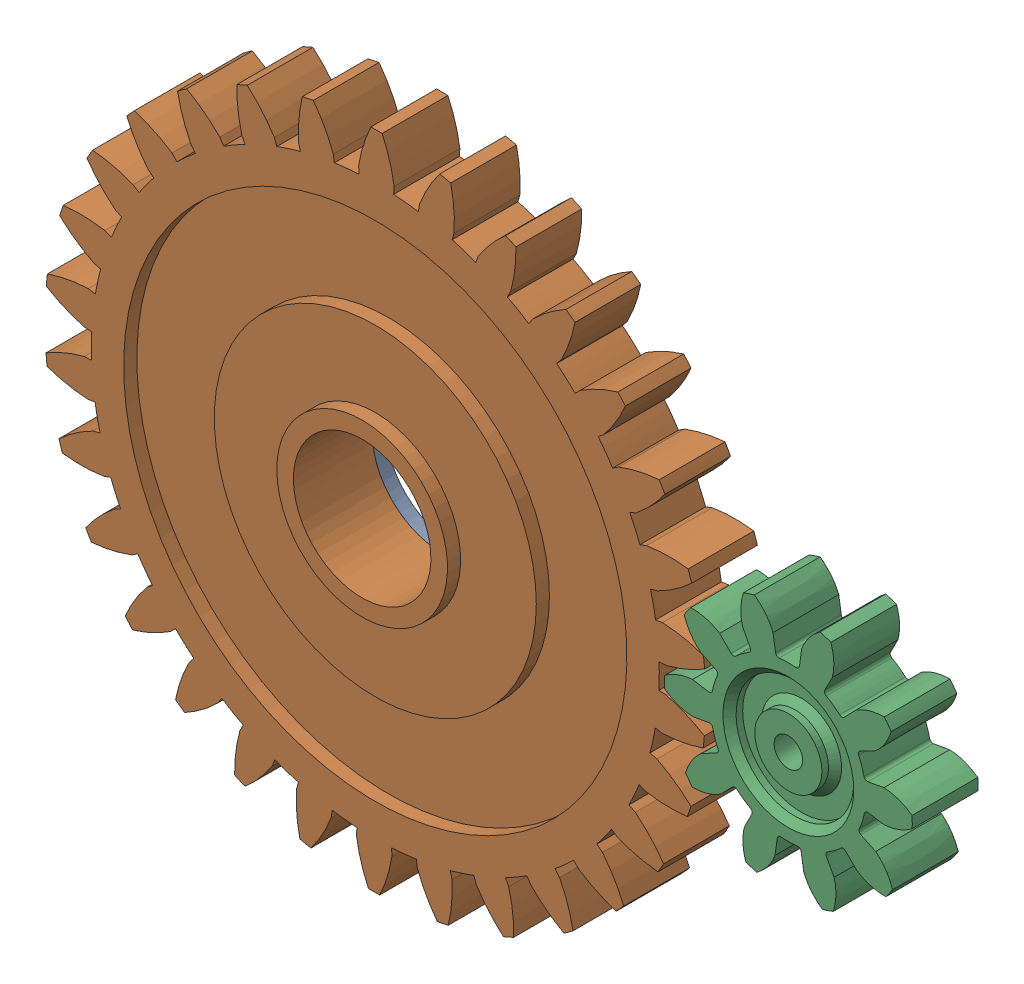
SolidWorks assembly gears assembly, configuration Default. Lengths in mm.
Overall size (152.64 129.51 14).
2 component instances, 2 part files, 5 mates.
Components (placement in the parent):
- Spur gear-1: Spur gear [Default] at (-0.6045 24.6881 0) x (-0.935315 0.353815 0) z (0 0 1) size (100.51 100.45 14)
- Pignon-1: Pignon [Default] at (62.2345 24.3345 0) x (-0.436797 -0.89956 0) z (0 0 1) size (37.51 37.44 10)
Mates (geometry in assembly coordinates):
- Concentric1: concentric aligned: circle of Pignon-1
- Coincident1: coincident aligned: plane of Spur gear-1 through (-0.6045 24.6881 10) normal (0 0 1); plane of Pignon-1 through (81.5215 13.5922 10) normal (0 0 1)
- Concentric2: concentric aligned: circle of Spur gear-1
- Coincident2: coincident anti-aligned: plane of Spur gear-1 through (-0.6045 24.6881 0) normal (0 0 -1)
- GearMate1: gear = 31.42 : 94.26 mm: circle of assembly; circle of assembly; circle of Pignon-1
